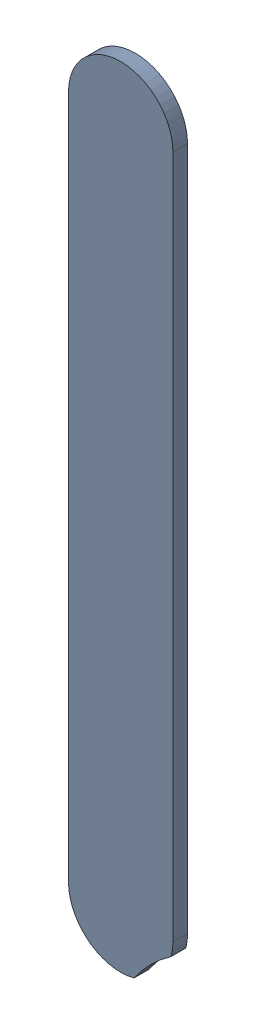
SolidWorks assembly Track (19.975mm,29.725mm)(19.975mm,31.391mm) on Top Layer, configuration Predeterminado. Lengths in mm.
Overall size (0.25 1.92 0.04).
2 component instances, 1 part files, 0 mates.
Components (placement in the parent):
- Track (19.975mm,29.725mm)(19.975mm,31.391mm) on Top Layer-1-1: Track (19.975mm,29.725mm)(19.975mm,31.391mm) on Top Layer-1 [Predeterminado] at (-68.317 -44.187 -0.0457) size (0.25 1.92 0.04)
  - Track (19.975mm,29.725mm)(19.975mm,31.391mm) on Top Layer-Part-1-1: Track (19.975mm,29.725mm)(19.975mm,31.391mm) on Top Layer-Part-1 [Predeterminado] at origin size (0.25 1.92 0.04)
